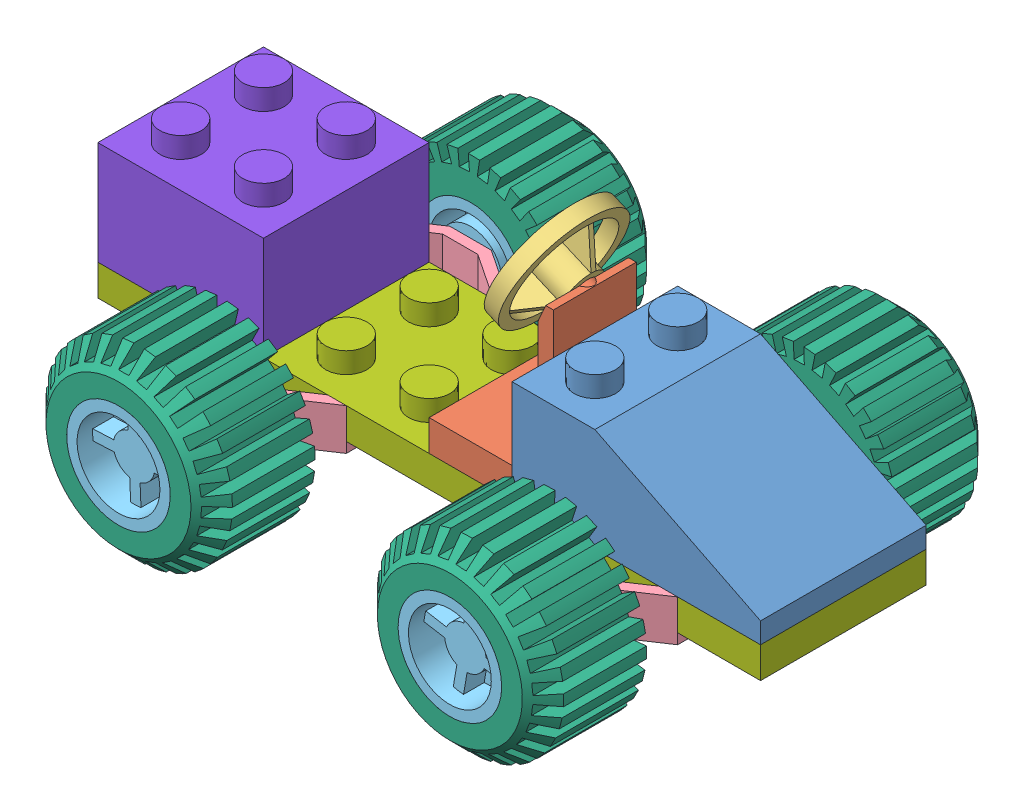
SolidWorks assembly Ensamblaje1, configuration Predeterminado. Lengths in mm.
Overall size (64 35.3 44).
15 component instances, 8 part files, 38 mates.
Components (placement in the parent):
- P3_2pines_triang-1: P3_2pines_triang [Default] at (-31.6529 22.6345 14.7) x (0 0 -1) z (1 0 0) size (16 12 24)
- P4_Base_Volante-1: P4_Base_Volante [Default] at (-59.6529 20.6345 14.7) x (0 0 1) z (-1 0 0) size (16 15.44 8)
- P5_Volante-1: P5_Volante [Default] at (-59.9844 35.1804 14.7) x (-0.051706 -0.118186 -0.991644) z (0.916157 -0.400819 0) size (11.8 11.8 3.5)
- P6_Ejes_Rueda-1: P6_Ejes_Rueda [Default] at (-79.6529 16.6345 14.7) x (0 0 -1) z (1 0 0) size (40 4 16)
- P7_Acople_Rueda-1: P7_Acople_Rueda [Default] at (-79.6529 18.6345 -2.3) x (0.87332 -0.487146 0) z (0 0 1) size (10 10 10)
- P8_Neumatico_Rueda-1: P8_Neumatico_Rueda [Default] at (-47.6529 18.6345 -7.3) x (0.428852 -0.903375 0) z (0 0 1) size (18 17.99 10)
- P1_16pines-1: P1_16pines [Default] at (-63.6529 17.6345 14.7) size (64 5 16)
- P2_4pines-1: P2_4pines [Default] at (-87.6529 20.6345 14.7) size (16 12 16)
- P6_Ejes_Rueda-2: P6_Ejes_Rueda [Default] at (-47.6529 16.6345 14.7) x (0 0 -1) z (1 0 0) size (40 4 16)
- P7_Acople_Rueda-2: P7_Acople_Rueda [Default] at (-79.6529 18.6345 31.7) x (-0.999047 -0.043655 0) z (0 0 -1) size (10 10 10)
- P7_Acople_Rueda-3: P7_Acople_Rueda [Default] at (-47.6529 18.6345 31.7) x (0.985377 -0.170388 0) z (0 0 -1) size (10 10 10)
- P7_Acople_Rueda-4: P7_Acople_Rueda [Default] at (-47.6529 18.6345 -2.3) x (0.585722 -0.810512 0) z (0 0 1) size (10 10 10)
- P8_Neumatico_Rueda-2: P8_Neumatico_Rueda [Default] at (-79.6529 18.6345 36.7) x (0.940108 -0.340877 0) z (0 0 -1) size (18 17.99 10)
- P8_Neumatico_Rueda-3: P8_Neumatico_Rueda [Default] at (-79.6529 18.6345 -7.3) x (0.659687 -0.751541 0) z (0 0 1) size (18 17.99 10)
- P8_Neumatico_Rueda-4: P8_Neumatico_Rueda [Default] at (-47.6529 18.6345 36.7) x (-0.655657 -0.755059 0) z (0 0 -1) size (18 17.99 10)
Mates (geometry in assembly coordinates):
- Coincidente1: coincident aligned: plane of P1_16pines-1 through (-31.6529 20.6345 22.7) normal (0 0 1); plane of P2_4pines-1 through (-79.6529 30.6345 22.7) normal (0 0 1)
- Coincidente2: coincident aligned: plane of P1_16pines-1 through (-95.6529 20.6345 22.7) normal (-1 0 0); plane of P2_4pines-1 through (-95.6529 30.6345 22.7) normal (-1 0 0)
- Coincidente3: coincident anti-aligned: plane of P1_16pines-1 through (-63.6529 20.6345 14.7) normal (0 1 0); plane of P2_4pines-1 through (-87.6529 20.6345 14.7) normal (0 -1 0)
- Coincidente5: coincident aligned: plane of P3_2pines_triang-1 through (-31.6529 22.6345 6.7) normal (1 0 0); plane of P1_16pines-1 through (-31.6529 20.6345 22.7) normal (1 0 0)
- Coincidente6: coincident aligned: plane of P3_2pines_triang-1 through (-31.6529 22.6345 22.7) normal (0 0 1); plane of P1_16pines-1 through (-31.6529 20.6345 22.7) normal (0 0 1)
- Coincidente7: coincident anti-aligned: plane of P3_2pines_triang-1 through (-31.6529 20.6345 6.7) normal (0 -1 0); plane of P1_16pines-1 through (-63.6529 20.6345 14.7) normal (0 1 0)
- Coincidente10: coincident aligned: plane of P4_Base_Volante-1 through (-63.6529 23.6345 22.7) normal (0 0 1); plane of P1_16pines-1 through (-31.6529 20.6345 22.7) normal (0 0 1)
- Coincidente11: coincident anti-aligned: plane of P3_2pines_triang-1 through (-55.6529 20.6345 6.7) normal (-1 0 0); plane of P4_Base_Volante-1 through (-55.6529 23.6345 22.7) normal (1 0 0)
- Coincidente12: coincident anti-aligned: plane of P4_Base_Volante-1 through (-59.6529 20.6345 14.7) normal (0 -1 0); plane of P1_16pines-1 through (-63.6529 20.6345 14.7) normal (0 1 0)
- Concéntrica1: concentric aligned: cylinder of P4_Base_Volante-1 through (499940.828 -218715.175 14.7) axis (-0.916157 0.400819 0) radius 1.2; cylinder of P5_Volante-1 through (-56.7779 33.7775 14.7) axis (-0.916157 0.400819 0) radius 1.2
- Coincidente13: coincident anti-aligned: plane of P4_Base_Volante-1 through (-56.4029 34.6345 6.7) normal (-0.916157 0.400819 0); plane of P5_Volante-1 through (-56.7779 33.7775 14.7) normal (0.916157 -0.400819 0)
- Coincidente15: coincident anti-aligned: plane of P6_Ejes_Rueda-1 through (-87.6529 20.6345 6.7) normal (0 0 1); plane of P1_16pines-1 through (-31.6529 20.6345 6.7) normal (0 0 -1)
- Coincidente16: coincident anti-aligned: plane of P6_Ejes_Rueda-1 through (-79.6529 17.6345 14.7) normal (0 1 0); plane of P1_16pines-1 through (-63.6529 17.6345 14.7) normal (0 -1 0)
- Coincidente19: coincident anti-aligned: plane of P1_16pines-1 through (-31.6529 20.6345 22.7) normal (0 0 1); plane of P6_Ejes_Rueda-2 through (-39.6529 20.6345 22.7) normal (0 0 -1)
- Coincidente20: coincident anti-aligned: plane of P1_16pines-1 through (-63.6529 17.6345 14.7) normal (0 -1 0); plane of P6_Ejes_Rueda-2 through (-47.6529 17.6345 14.7) normal (0 1 0)
- Concéntrica2: concentric aligned: cylinder of P1_16pines-1 through (-43.6529 22.6345 18.7) axis (0 -1 0) radius 1; cylinder of P6_Ejes_Rueda-2 through (-43.6529 19.6345 18.7) axis (0 -1 0) radius 2
- Concéntrica3: concentric aligned: cylinder of P6_Ejes_Rueda-1 through (-83.6529 19.6345 10.7) axis (0 -1 0) radius 2; cylinder of P1_16pines-1 through (-83.6529 22.6345 10.7) axis (0 -1 0) radius 1
- Concéntrica4: concentric aligned: cylinder of P6_Ejes_Rueda-2 through (-47.6529 18.6345 34.7) axis (0 0 -1) radius 1.5; cylinder of P7_Acople_Rueda-3 through (-47.6529 18.6345 34.7) axis (0 0 -1) radius 1.5
- Coincidente21: coincident anti-aligned: plane of P6_Ejes_Rueda-2 through (-45.6529 17.6345 26.7) normal (0 0 1); plane of P7_Acople_Rueda-3 through (-48.1641 15.6784 26.7) normal (0 0 -1)
- Concéntrica5: concentric aligned: cylinder of P6_Ejes_Rueda-1 through (-79.6529 18.6345 34.7) axis (0 0 -1) radius 1.5; cylinder of P7_Acople_Rueda-2 through (-79.6529 18.6345 34.7) axis (0 0 -1) radius 1.5
- Coincidente22: coincident anti-aligned: plane of P6_Ejes_Rueda-1 through (-77.6529 17.6345 26.7) normal (0 0 1); plane of P7_Acople_Rueda-2 through (-79.7839 21.6316 26.7) normal (0 0 -1)
- Concéntrica6: concentric aligned: cylinder of P6_Ejes_Rueda-2 through (-47.6529 18.6345 -5.3) axis (0 0 1) radius 1.5; cylinder of P7_Acople_Rueda-4 through (-47.6529 18.6345 -5.3) axis (0 0 1) radius 1.5
- Concéntrica7: concentric aligned: cylinder of P6_Ejes_Rueda-1 through (-79.6529 18.6345 -5.3) axis (0 0 1) radius 1.5; cylinder of P7_Acople_Rueda-1 through (-79.6529 18.6345 -5.3) axis (0 0 1) radius 1.5
- Coincidente23: coincident anti-aligned: plane of P6_Ejes_Rueda-2 through (-45.6529 17.6345 2.7) normal (0 0 -1); plane of P7_Acople_Rueda-4 through (-50.3905 19.8617 2.7) normal (0 0 1)
- Coincidente24: coincident anti-aligned: plane of P6_Ejes_Rueda-1 through (-77.6529 17.6345 2.7) normal (0 0 -1); plane of P7_Acople_Rueda-1 through (-78.1915 21.2545 2.7) normal (0 0 1)
- Concéntrica8: concentric anti-aligned: cylinder of P7_Acople_Rueda-1 through (-79.6529 18.6345 6.1354) axis (0 0 1) radius 5; cylinder of P8_Neumatico_Rueda-3 through (-79.6529 18.6345 2.7) axis (0 0 -1) radius 5
- Coincidente25: coincident aligned: plane of P7_Acople_Rueda-1 through (-77.7044 22.1278 -7.3) normal (0 0 -1); plane of P8_Neumatico_Rueda-3 through (-79.6529 18.6345 -7.3) normal (0 0 -1)
- Concéntrica9: concentric anti-aligned: cylinder of P8_Neumatico_Rueda-1 through (-47.6529 18.6345 2.7) axis (0 0 -1) radius 5; cylinder of P7_Acople_Rueda-4 through (-47.6529 18.6345 6.1354) axis (0 0 1) radius 5
- Coincidente26: coincident aligned: plane of P8_Neumatico_Rueda-1 through (-47.6529 18.6345 -7.3) normal (0 0 -1); plane of P7_Acople_Rueda-4 through (-51.303 20.2707 -7.3) normal (0 0 -1)
- Concéntrica10: concentric anti-aligned: cylinder of P7_Acople_Rueda-2 through (-79.6529 18.6345 23.2646) axis (0 0 -1) radius 5; cylinder of P8_Neumatico_Rueda-2 through (-79.6529 18.6345 26.7) axis (0 0 1) radius 5
- Concéntrica11: concentric anti-aligned: cylinder of P7_Acople_Rueda-3 through (-47.6529 18.6345 23.2646) axis (0 0 -1) radius 5; cylinder of P8_Neumatico_Rueda-4 through (-47.6529 18.6345 26.7) axis (0 0 1) radius 5
- Coincidente27: coincident aligned: plane of P7_Acople_Rueda-2 through (-79.8276 22.6307 36.7) normal (0 0 1); plane of P8_Neumatico_Rueda-2 through (-79.6529 18.6345 36.7) normal (0 0 1)
- Coincidente28: coincident aligned: plane of P7_Acople_Rueda-3 through (-48.3345 14.693 36.7) normal (0 0 1); plane of P8_Neumatico_Rueda-4 through (-47.6529 18.6345 36.7) normal (0 0 1)
- Bloquear1: lock: unknown of P7_Acople_Rueda-2; unknown of P8_Neumatico_Rueda-2
- Coincidente29: coincident aligned: plane of P7_Acople_Rueda-3 through (-48.3345 14.693 36.7) normal (0 0 1); plane of P8_Neumatico_Rueda-4 through (-47.6529 18.6345 36.7) normal (0 0 1)
- Bloquear2: lock: unknown of P7_Acople_Rueda-3; unknown of P8_Neumatico_Rueda-4
- Bloquear3: lock: unknown of P8_Neumatico_Rueda-1; unknown of P7_Acople_Rueda-4
- Bloquear4: lock: unknown of P7_Acople_Rueda-1; unknown of P8_Neumatico_Rueda-3
